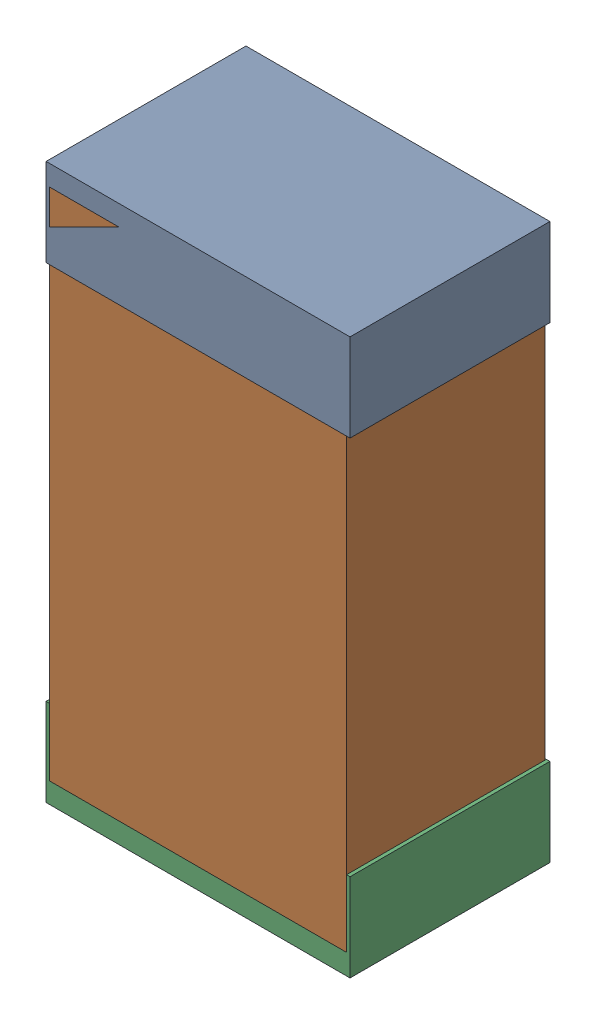
SolidWorks assembly R45Kanaloa_v2.0.0_Motor, configuration Default. Lengths in mm.
Overall size (1.3 2.38 0.85).
6 component instances, 2 part files, 0 mates.
Components (placement in the parent):
- 330415056-1: 330415056 [Default] at (124.46 120.634 -1.9574) size (1.3 0.38 0.85)
  - Extruded_2-1: Extruded_2 [Default] at origin size (1.3 0.38 0.85)
- 334787376-1: 334787376 [Default] at (124.46 119.634 -1.9524) size (1.27 2.2 0.85)
  - Extruded_16-1: Extruded_16 [Default] at origin size (1.27 2.2 0.85)
- 330415056-2: 330415056 [Default] at (124.46 118.634 -1.9574) size (1.3 0.38 0.85)
  - Extruded_2-1: Extruded_2 [Default] at origin size (1.3 0.38 0.85)
